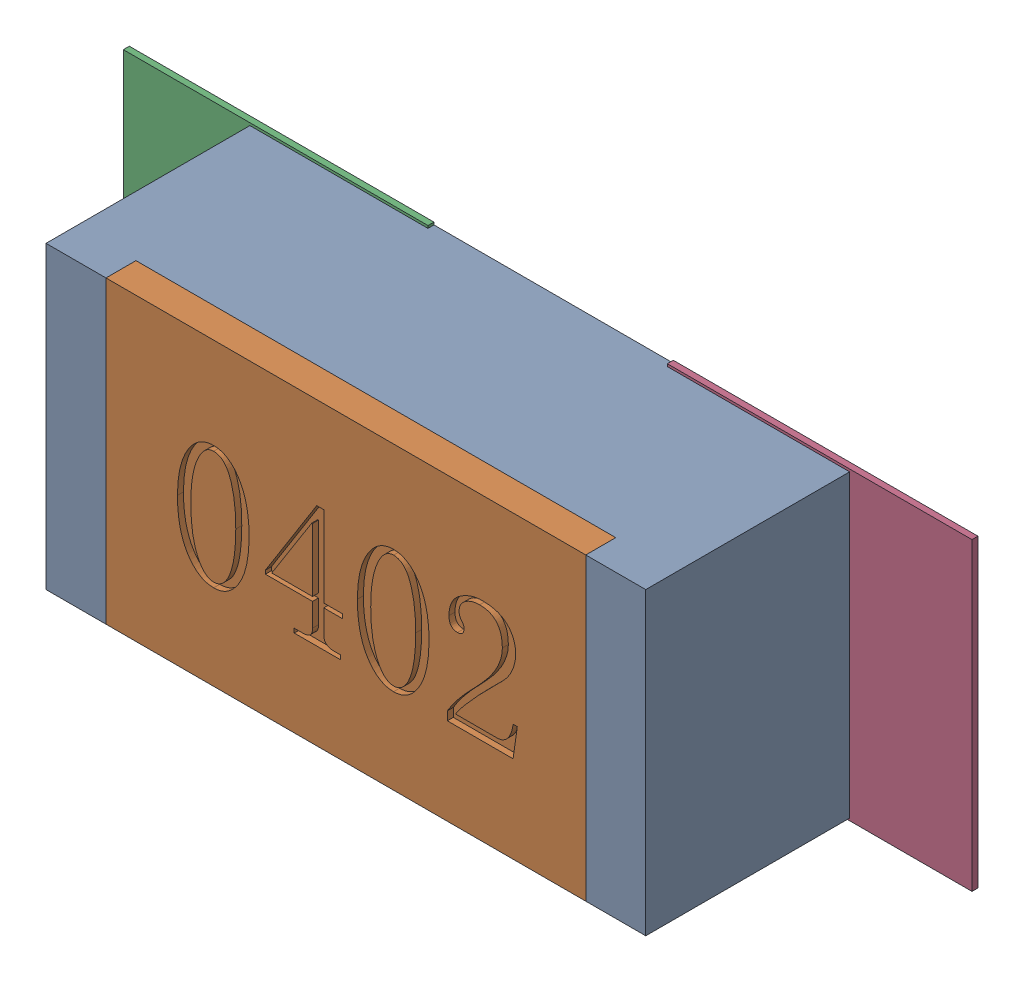
SolidWorks assembly R23, configuration Défaut. Lengths in mm.
Overall size (1.42 0.51 0.35).
5 component instances, 2 part files, 0 mates.
Components (placement in the parent):
- R0402-1: R0402 [Défaut] at (45.8747 -8.9342 0) x (1 0 0) z (0 0 1) size (1 0.5 0.35)
- 6504207776-1: 6504207776 [Défaut] at (45.4176 -8.9341 0) size (0.51 0.51 0.01)
  - Extruded-1: Extruded [Défaut] at origin size (0.51 0.51 0.01)
- 6504207776-2: 6504207776 [Défaut] at (46.3247 -8.9341 0) size (0.51 0.51 0.01)
  - Extruded-1: Extruded [Défaut] at origin size (0.51 0.51 0.01)
